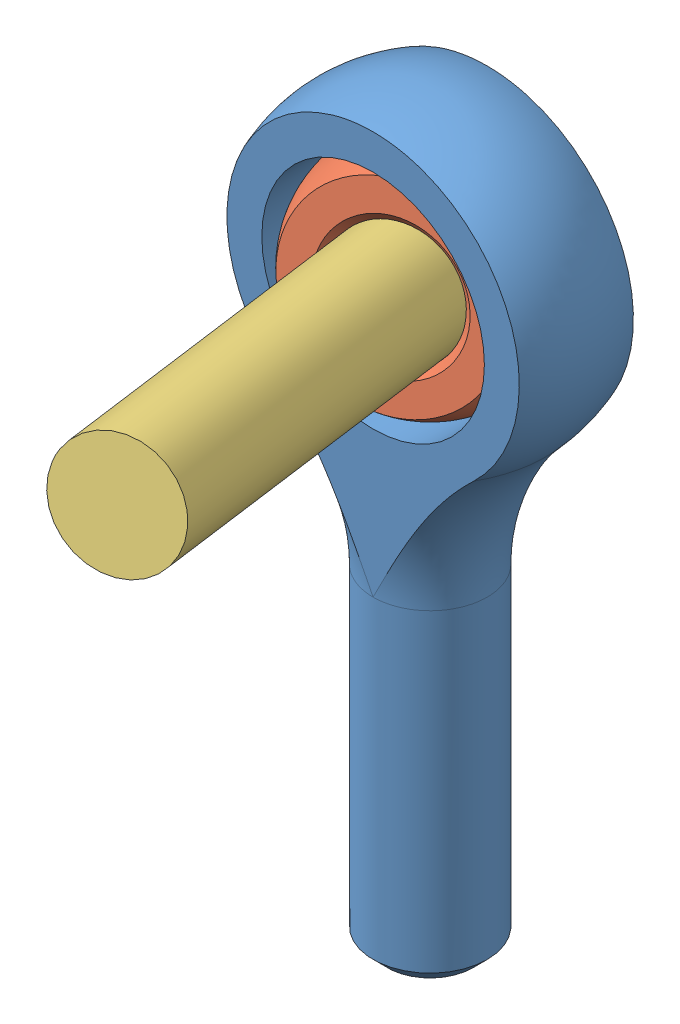
SolidWorks assembly 0.5 INCH ROD END, configuration Default. Lengths in mm.
Overall size (19.45 41.28 31.19).
3 component instances, 3 part files, 9 mates.
Components (placement in the parent):
- 1_2-Heim_60645K181-3: 1_2-Heim_60645K181 [60645K181] at (-2.8109 40.4768 90.3868) size (17.46 41.27 6.35)
- 1_2-Ball-60645K181-1: 1_2-Ball-60645K181 [60645K181] at (-2.8109 58.4317 90.3868) x (-0.957408 0.159075 0.240965) z (0.265637 0.158184 0.951007) size (12.15 12.15 6.35)
- rod part-1: rod part [Default] at (-3.6542 57.9295 87.3673) x (-0.355571 -0.900828 0.249156) z (-0.896106 0.404335 0.183047) size (6.35 28.57 6.35)
Mates (geometry in assembly coordinates):
- Coincident2: coincident: plane of ?; plane of 1_2-Heim_60645K181-3 through (-8.1333 53.8543 95.6339) normal (0 0 1)
- Coincident4: coincident aligned: plane of 1_2-Heim_60645K181-3; plane of 1_2-Heim_60645K181-3 through (-2.8109 40.4768 90.3868) normal (1 0 0)
- Concentric1: concentric: sphere of 1_2-Heim_60645K181-3; sphere of ?
- LimitAngle1: limit planar angle = 0.149787 rad aligned: cylinder of ? through (-4.4141 68.6281 79.3987) axis (0.144273 0.038133 0.988803) radius 9.525; cylinder of 1_2-Heim_60645K181-3 through (-2.8109 69.0518 84.0368) axis (0 0 1) radius 9.525
- Concentric2: concentric: sphere of 1_2-Heim_60645K181-3; sphere of 1_2-Ball-60645K181-1
- LimitAngle2: limit planar angle = 0.314318 rad aligned: cylinder of 1_2-Ball-60645K181-1 through (-3.6542 57.9295 87.3673) axis (0.265637 0.158184 0.951007) radius 3.175; cylinder of 1_2-Heim_60645K181-3 through (-2.8109 58.4317 87.2118) axis (0 0 1) radius 6.1913
- LimitAngle3: limit planar angle = 0.314318 rad aligned: plane of 1_2-Ball-60645K181-1 through (0.9763 33.2147 96.862) normal (0.265637 0.158184 0.951007); plane of 1_2-Heim_60645K181-3 through (-11.5421 67.163 93.5618) normal (0 0 1)
- Coincident6: coincident aligned: plane of 1_2-Ball-60645K181-1 through (-0.7105 32.2102 90.8231) normal (-0.265637 -0.158184 -0.951007); plane of rod part-1 through (-3.6542 57.9295 87.3673) normal (-0.265637 -0.158184 -0.951007)
- Concentric3: concentric anti-aligned: cylinder of 1_2-Ball-60645K181-1 through (-3.6542 57.9295 87.3673) axis (0.265637 0.158184 0.951007) radius 3.175; cylinder of rod part-1 through (3.9363 62.4496 114.5424) axis (-0.265637 -0.158184 -0.951007) radius 3.175
